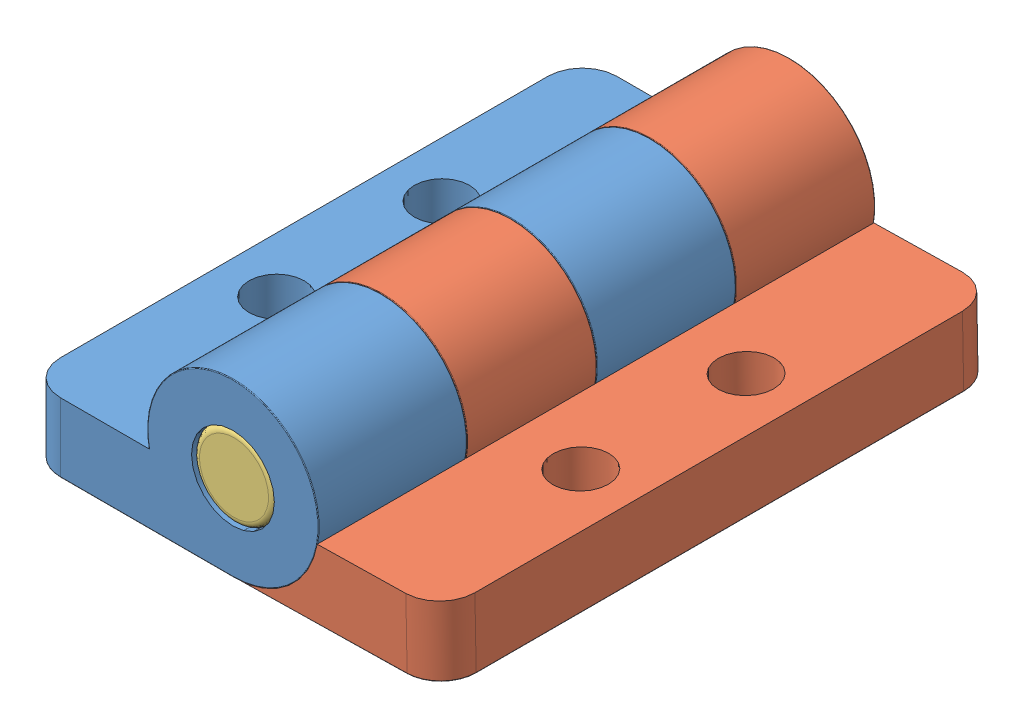
SolidWorks assembly Hinge, configuration Default. Lengths in mm.
Overall size (30.11 12.79 40.38).
3 component instances, 3 part files, 3 mates.
Components (placement in the parent):
- Half Hinge-1: Half Hinge [Default] at (5.3085 21.6257 20.1599) size (21.2 12.4 40.3)
- Half Hinge2-1: Half Hinge2 [Default] at (5.3085 21.6257 20.1599) x (0.999828 0.018555 0) z (0 0 1) size (21.2 12.4 40.3)
- Pin-1: Pin [Default] at (5.3085 21.6257 20.0819) x (0.998563 0.053585 0) z (0 0 1) size (6 6 40.3)
Mates (geometry in assembly coordinates):
- Coincident1: coincident anti-aligned: plane of Half Hinge2-1 through (5.3085 21.6257 40.3099) normal (0 0 -1); plane of Half Hinge-1 through (5.3085 21.6257 40.3099) normal (0 0 1)
- Concentric1: concentric aligned: cylinder of Half Hinge-1 through (5.3085 21.6257 60.4599) axis (0 0 -1) radius 3; cylinder of Pin-1 through (5.3085 21.6257 60.3819) axis (0 0 -1) radius 3
- Concentric2: concentric aligned: circle of Half Hinge-1; circle of Half Hinge2-1
